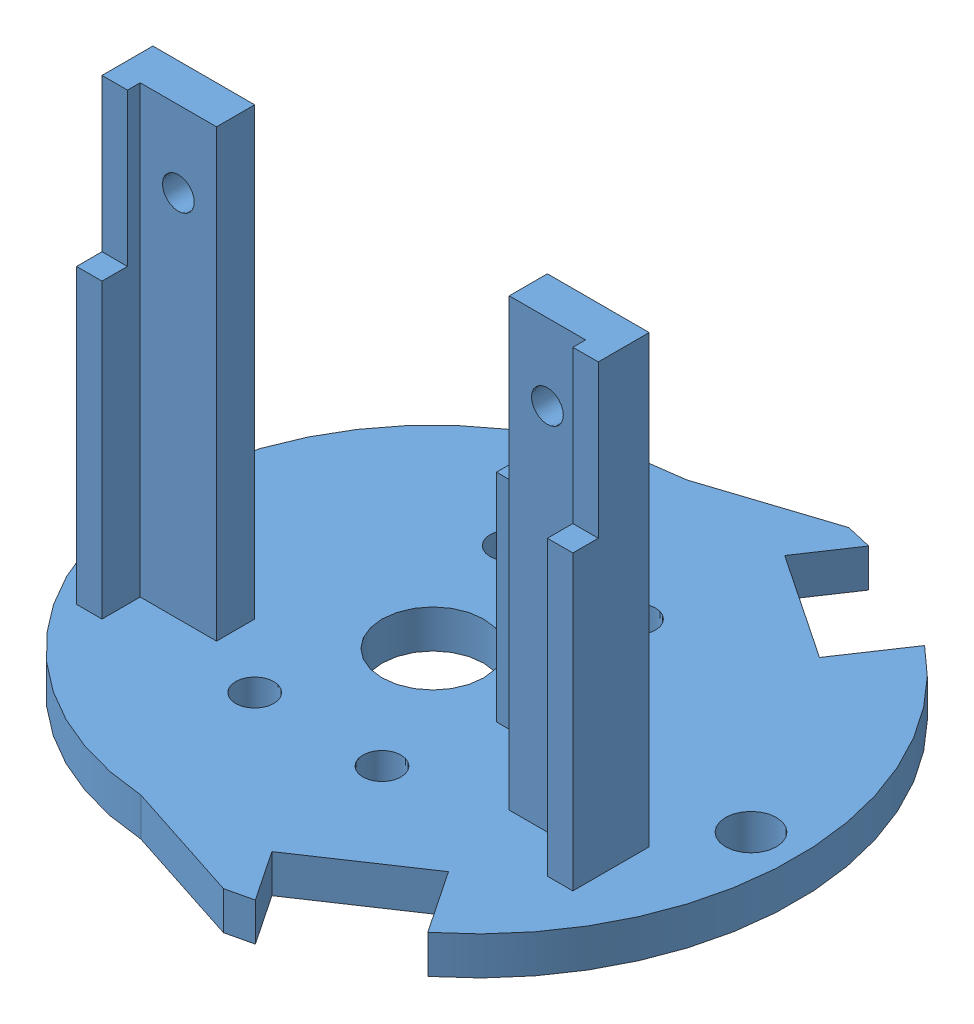
SolidWorks assembly Rückseite, configuration Standard. Lengths in mm.
Overall size (50 38 49.14).
19 component instances, 10 part files, 39 mates.
Components (placement in the parent):
- Backside-1: Backside [Standard] at (-0.7502 -6.4244 50) size (50 38 49.14)
- servo-1: servo [Standard] at (-9.7502 31.5756 70.5) x (1 0 0) z (0 1 0) size (33 29.25 12) (hidden)
- Drücker-1: Drücker [Standard] at (-2.5879 9.7207 78.2478) x (1 0 0) z (0 0 -1) size (8 29 8) (hidden)
- Hebel-1: Hebel [Standard] at (9.2498 10.5756 51) x (0.948067 0.318072 0) z (0 0 -1) size (29.78 9.71 13) (hidden)
- Servo-Arm-1: Servo-Arm [Standard] at (7.2498 25.5756 39.25) x (0.97277 -0.231775 0) z (-0.231775 -0.97277 0) size (20.6 4.3 7.2) (hidden)
- Hebel2-1: Hebel2 [Standard] at (19.7094 8.1296 39.25) x (-0.117277 0.993099 0) z (0.993099 0.117277 0) size (21 6 6) (hidden)
- User Library-Mutter DIN-985_-1: User Library-Mutter DIN-985_ [Mutter DIN-985 M3-A2] at (-4.7502 -3.4244 60) x (0 1 0) z (-0.455135 0 0.890422) size (4 6.35 5.5) (hidden)
- User Library-Mutter DIN-985_-2: User Library-Mutter DIN-985_ [Mutter DIN-985 M3-A2] at (5.2498 -3.4244 60) x (0 1 0) z (-0.871788 0 0.489884) size (4 6.35 5.5) (hidden)
- User Library-Mutter DIN-985_-3: User Library-Mutter DIN-985_ [Mutter DIN-985 M3-A2] at (5.2498 -3.4244 40) x (0 1 0) z (-0.77566 0 0.631152) size (4 6.35 5.5) (hidden)
- User Library-Mutter DIN-985_-4: User Library-Mutter DIN-985_ [Mutter DIN-985 M3-A2] at (-4.7502 -3.4244 40) x (0 1 0) z (-0.229708 0 0.97326) size (4 6.35 5.5) (hidden)
- socket head cap screw 4762_din-1: socket head cap screw 4762_din [ISO 4762 M2 x 10 --- 10S] at (9.2498 10.5756 45.5) x (0 0 1) z (0 -1 0) size (12 3.8 3.8) (hidden)
- socket head cap screw 4762_din-2: socket head cap screw 4762_din [ISO 4762 M2 x 10 --- 10S] at (-0.7502 7.2207 55) x (0 0 -1) z (0.809309 -0.587383 0) size (12 3.8 3.8) (hidden)
- socket head cap screw 4762_din-3: socket head cap screw 4762_din [ISO 4762 M2 x 10 --- 10S] at (17.9503 23.0261 45.25) x (0 0 -1) z (-0.325588 0.945512 0) size (12 3.8 3.8) (hidden)
- nut__style_1__m2x0_4__ansi_b18_2_4_1m-1: nut__style_1__m2x0_4__ansi_b18_2_4_1m [Default] at (-0.7502 7.2207 47) x (0.83114 0.556064 0) z (0 0 -1) size (4.62 4 1.6) (hidden)
- nut__style_1__m2x0_4__ansi_b18_2_4_1m-2: nut__style_1__m2x0_4__ansi_b18_2_4_1m [Default] at (17.9503 23.0261 35.65) x (0.980747 -0.195284 0) z (0 0 1) size (4.62 4 1.6) (hidden)
- nut__style_1__m2x0_4__ansi_b18_2_4_1m-3: nut__style_1__m2x0_4__ansi_b18_2_4_1m [Default] at (9.2498 10.5756 52.5) x (0.980747 -0.195284 0) z (0 0 1) size (4.62 4 1.6) (hidden)
- User Library-Mutter DIN-985_-5: User Library-Mutter DIN-985_ [Mutter DIN-985 M2,5-A2] at (-12.7502 25.5756 58) x (0 0 1) z (0.965495 0.260421 0) size (3.8 5.77 5) (hidden)
- User Library-Mutter DIN-985_-6: User Library-Mutter DIN-985_ [Mutter DIN-985 M2,5-A2] at (16.2498 25.5756 58) x (0 0 1) z (-0.395566 -0.918438 0) size (3.8 5.77 5) (hidden)
- oval head sheet metal screw_din-1: oval head sheet metal screw_din [Tapping screw DIN 7983-ST2.9x6.5-F-H-S] at (7.2498 25.5756 40.6565) x (0 0 1) z (-0.615967 -0.787772 0) size (7.15 5.82 5.82) (hidden)
Mates (geometry in assembly coordinates):
- Konzentrisch1: concentric anti-aligned: cylinder of Drücker-1 through (-0.7502 -19.2793 50) axis (0 1 0) radius 4; cylinder of Backside-1 through (-0.7502 -3.4244 50) axis (0 -1 0) radius 4
- Konzentrisch2: concentric aligned: cylinder of Backside-1 through (9.2498 10.5756 42.5) axis (0 0 1) radius 1; cylinder of Hebel-1 through (9.2498 10.5756 49) axis (0 0 1) radius 1
- Deckungsgleich1: coincident anti-aligned: plane of Hebel-1; plane of Backside-1 through (6.7498 13.5756 49) normal (0 0 1)
- Parallel1: parallel anti-aligned: plane of Drücker-1 through (-5.7502 1.7207 51) normal (0 0 -1); plane of Hebel-1 through (9.2498 10.5756 51) normal (0 0 1)
- Tangential1: tangent anti-aligned: cylinder of Drücker-1 through (-0.7502 7.2207 54) axis (0 0 -1) radius 1; plane of Hebel-1 through (8.9317 11.5237 49) normal (0.318072 -0.948067 0)
- Konzentrisch3: concentric anti-aligned: cylinder of servo-1 through (7.2498 25.5756 44) axis (0 0 1) radius 6; cylinder of Servo-Arm-1 through (7.2498 25.5756 43.55) axis (0 0 -1) radius 2.25
- Deckungsgleich6: coincident anti-aligned: plane of Backside-1 through (-9.7502 31.5756 58) normal (1 0 0); plane of servo-1 through (-9.7502 31.5756 48) normal (-1 0 0)
- Deckungsgleich7: coincident anti-aligned: plane of Backside-1 through (-9.7502 31.5756 55) normal (0 0 -1); plane of servo-1 through (18.2498 31.5756 55) normal (0 0 1)
- Deckungsgleich11: coincident aligned: plane of Backside-1 through (-0.7502 31.5756 50) normal (0 1 0); plane of servo-1 through (-9.7502 31.5756 48) normal (0 1 0)
- Deckungsgleich9: coincident anti-aligned: plane of Servo-Arm-1 through (7.2498 25.5756 39.25) normal (0 0 -1); plane of Hebel2-1 through (19.7094 8.1296 39.25) normal (0 0 1)
- Konzentrisch4: concentric anti-aligned: cylinder of Hebel-1 through (19.7094 8.1296 38) axis (0 0 1) radius 1; cylinder of Hebel2-1 through (19.7094 8.1296 41.25) axis (0 0 -1) radius 1
- Deckungsgleich12: coincident anti-aligned: plane of servo-1 through (7.2498 25.5756 41.25) normal (0 0 -1); plane of Servo-Arm-1 through (7.2498 25.5756 41.25) normal (0 0 1)
- Konzentrisch5: concentric aligned: cylinder of Servo-Arm-1 through (17.9503 23.0261 41.25) axis (0 0 -1) radius 0.5; cylinder of Hebel2-1 through (17.9503 23.0261 41.25) axis (0 0 -1) radius 1
- Deckungsgleich28: coincident anti-aligned: plane of Backside-1 through (-0.7502 -3.4244 50) normal (0 1 0); plane of User Library-Mutter DIN-985_-1 through (-7.1799 -3.4244 58.7581) normal (0 -1 0)
- Deckungsgleich29: coincident anti-aligned: plane of Backside-1 through (-0.7502 -3.4244 50) normal (0 1 0); plane of User Library-Mutter DIN-985_-2 through (3.9131 -3.4244 57.6211) normal (0 -1 0)
- Deckungsgleich31: coincident anti-aligned: plane of Backside-1 through (-0.7502 -3.4244 50) normal (0 1 0); plane of User Library-Mutter DIN-985_-3 through (3.5276 -3.4244 37.8834) normal (0 -1 0)
- Deckungsgleich30: coincident anti-aligned: plane of Backside-1 through (-0.7502 -3.4244 50) normal (0 1 0); plane of User Library-Mutter DIN-985_-4 through (-7.4059 -3.4244 39.3732) normal (0 -1 0)
- Deckungsgleich21: coincident anti-aligned: plane of Backside-1 through (6.7498 13.5756 47.5) normal (0 0 -1); plane of socket head cap screw 4762_din-1 through (7.3498 10.5756 47.5) normal (0 0 1)
- Konzentrisch20: concentric anti-aligned: cylinder of Backside-1 through (9.2498 10.5756 42.5) axis (0 0 1) radius 1; cylinder of socket head cap screw 4762_din-1 through (9.2498 10.5756 13.75) axis (0 0 -1) radius 1
- Konzentrisch19: concentric anti-aligned: cylinder of Drücker-1 through (-0.7502 7.2207 54) axis (0 0 -1) radius 1; cylinder of socket head cap screw 4762_din-2 through (-0.7502 7.2207 86.75) axis (0 0 1) radius 1
- Deckungsgleich38: coincident anti-aligned: plane of Hebel2-1 through (19.7094 8.1296 43.25) normal (0 0 1); plane of socket head cap screw 4762_din-3 through (16.1538 22.4075 43.25) normal (0 0 -1)
- Konzentrisch38: concentric anti-aligned: cylinder of Hebel2-1 through (17.9503 23.0261 41.25) axis (0 0 -1) radius 1; cylinder of socket head cap screw 4762_din-3 through (17.9503 23.0261 77) axis (0 0 1) radius 1
- Deckungsgleich41: coincident anti-aligned: plane of Drücker-1 through (4.2498 1.7207 47) normal (0 0 -1); plane of nut__style_1__m2x0_4__ansi_b18_2_4_1m-1 through (1.1698 8.5052 47) normal (0 0 1)
- Konzentrisch49: concentric aligned: circle of socket head cap screw 4762_din-2; circle of nut__style_1__m2x0_4__ansi_b18_2_4_1m-1
- Deckungsgleich39: coincident anti-aligned: plane of Hebel2-1 through (19.7094 8.1296 37.25) normal (0 0 -1); plane of nut__style_1__m2x0_4__ansi_b18_2_4_1m-2 through (20.2158 22.575 37.25) normal (0 0 1)
- Konzentrisch50: concentric anti-aligned: circle of socket head cap screw 4762_din-3; circle of nut__style_1__m2x0_4__ansi_b18_2_4_1m-2
- Deckungsgleich33: coincident anti-aligned: plane of Backside-1 through (6.7498 13.5756 52.5) normal (0 0 1); plane of nut__style_1__m2x0_4__ansi_b18_2_4_1m-3 through (11.5153 10.1245 52.5) normal (0 0 -1)
- Konzentrisch48: concentric aligned: circle of socket head cap screw 4762_din-1; circle of nut__style_1__m2x0_4__ansi_b18_2_4_1m-3
- Deckungsgleich36: coincident anti-aligned: plane of Backside-1 through (-9.7502 31.5756 58) normal (0 0 1); plane of User Library-Mutter DIN-985_-5 through (-12.1447 23.3307 58) normal (0 0 -1)
- Deckungsgleich37: coincident anti-aligned: plane of Backside-1 through (13.2498 31.5756 58) normal (0 0 1); plane of User Library-Mutter DIN-985_-6 through (14.1143 26.4954 58) normal (0 0 -1)
- Konzentrisch51: concentric aligned: circle of Backside-1; circle of User Library-Mutter DIN-985_-1
- Konzentrisch52: concentric aligned: circle of Backside-1; circle of User Library-Mutter DIN-985_-2
- Konzentrisch53: concentric aligned: circle of Backside-1; circle of User Library-Mutter DIN-985_-4
- Konzentrisch54: concentric aligned: circle of Backside-1; circle of User Library-Mutter DIN-985_-3
- Konzentrisch55: concentric anti-aligned: circle of Backside-1; circle of User Library-Mutter DIN-985_-5
- Konzentrisch56: concentric anti-aligned: circle of Backside-1; circle of User Library-Mutter DIN-985_-6
- Deckungsgleich40: coincident anti-aligned: plane of Drücker-1 through (4.2498 1.7207 53) normal (0 0 1); plane of socket head cap screw 4762_din-2 through (0.3658 8.7584 53) normal (0 0 -1)
- Konzentrisch58: concentric anti-aligned: circle of Servo-Arm-1; circle of oval head sheet metal screw_din-1
- Tangential8: tangent: plane of Servo-Arm-1 through (7.2498 25.5756 39.25) normal (0 0 -1); circle of oval head sheet metal screw_din-1
